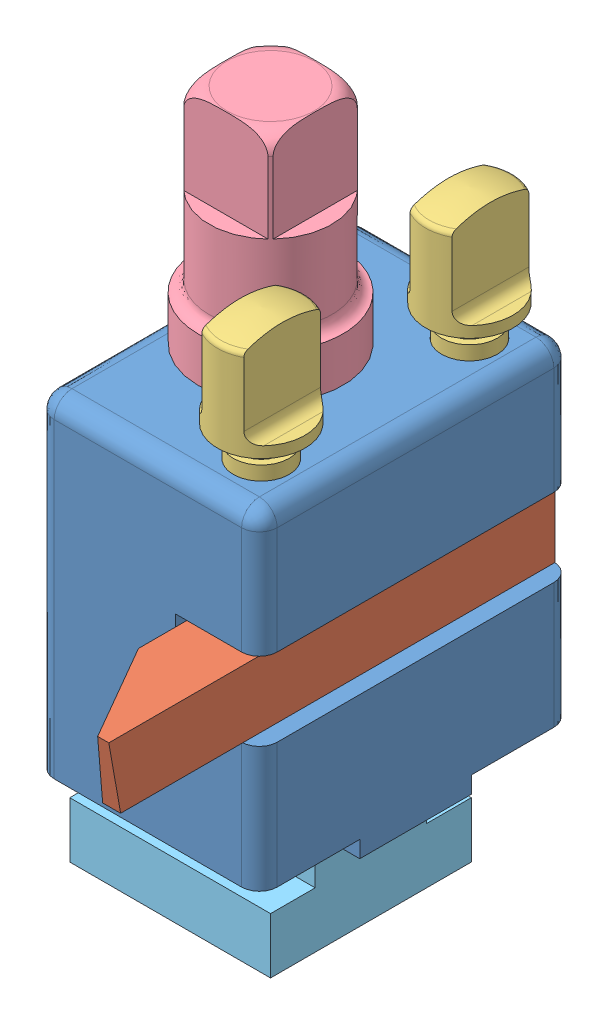
SolidWorks assembly Sub_Assembly_Tool_Post_R, configuration Default. Lengths in mm.
Overall size (34.92 96.23 63.5).
6 component instances, 5 part files, 13 mates.
Components (placement in the parent):
- Tool_Post-1: Tool_Post [Default] at (19.3679 28.1926 36.3512) size (31.75 49.21 44.45)
- Cutter-2: Cutter [Default] at (23.3366 22.6363 14.1262) x (-1 0 0) z (0 0 -1) size (9.53 9.53 63.5)
- Set_Screw-3: Set_Screw [Default] at (28.0991 32.1613 51.1678) size (12.45 38.14 12.45)
- Set_Screw-4: Set_Screw [Default] at (28.0991 32.1613 21.5345) size (12.45 38.14 12.45)
- Bolt-2: Bolt [Default] at (14.6054 -8.7168 36.3512) size (20.64 92.64 20.64)
- Tool_Block_Nut-2: Tool_Block_Nut [Default] at (14.6054 -12.3045 36.3512) size (28.57 11.91 28.57)
Mates (geometry in assembly coordinates):
- Distance2: distance = 0 mm aligned: plane of Cutter-2 through (32.8616 32.1613 14.1262) normal (0 0 -1); plane of Tool_Post-1 through (19.3679 28.1926 14.1262) normal (0 0 -1)
- Distance3: distance = 0 mm anti-aligned: plane of Cutter-2 through (23.3366 22.6363 14.1262) normal (0 -1 0); plane of Tool_Post-1 through (35.2429 22.6363 58.5762) normal (0 1 0)
- Distance4: distance = 0 mm anti-aligned: plane of Tool_Post-1 through (23.3366 33.7488 58.5762) normal (1 0 0); plane of Cutter-2 through (23.3366 32.1613 14.1262) normal (-1 0 0)
- Concentric1: concentric anti-aligned: cylinder of Tool_Post-1 through (28.0991 2.3947 51.1678) axis (0 1 0) radius 3.9688; cylinder of Set_Screw-3 through (28.0991 32.1613 51.1678) axis (0 -1 0) radius 3.9688
- Distance5: distance = 0 mm anti-aligned: plane of Set_Screw-3 through (28.0991 32.1613 51.1678) normal (0 -1 0); plane of Cutter-2 through (23.3366 32.1613 14.1262) normal (0 1 0)
- Parallel1: parallel aligned: plane of Tool_Post-1 through (35.2429 51.6082 58.5762) normal (1 0 0); plane of Set_Screw-3 through (31.0836 59.1488 44.9448) normal (1 0 0)
- Concentric2: concentric anti-aligned: cylinder of Tool_Post-1 through (28.0991 2.3947 21.5345) axis (0 1 0) radius 3.9688; cylinder of Set_Screw-4 through (28.0991 32.1613 21.5345) axis (0 -1 0) radius 3.9688
- Coincident7: coincident anti-aligned: plane of Cutter-2 through (23.3366 32.1613 14.1262) normal (0 1 0); plane of Set_Screw-4 through (28.0991 32.1613 21.5345) normal (0 -1 0)
- Parallel2: parallel aligned: plane of Tool_Post-1 through (35.2429 51.6082 58.5762) normal (1 0 0); plane of Set_Screw-4 through (31.0836 59.1488 15.3115) normal (1 0 0)
- Concentric3: concentric anti-aligned: cylinder of Tool_Post-1 through (14.6054 2.3957 36.3512) axis (0 1 0) radius 6.331; cylinder of Bolt-2 through (14.6054 -8.7168 36.3512) axis (0 -1 0) radius 6.331
- Coincident9: coincident anti-aligned: plane of Tool_Post-1 through (35.2429 51.6082 58.5762) normal (0 1 0); plane of Bolt-2 through (24.9241 51.6082 36.3512) normal (0 -1 0)
- Concentric4: concentric anti-aligned: cylinder of Bolt-2 through (14.6054 -8.7168 36.3512) axis (0 -1 0) radius 6.331; cylinder of Tool_Block_Nut-2 through (14.6054 -12.3045 36.3512) axis (0 1 0) radius 6.331
- Distance6: distance = 2.794 mm anti-aligned: plane of Tool_Block_Nut-2 through (0.3179 -0.3983 28.4137) normal (0 1 0); plane of Tool_Post-1 through (3.4929 2.3957 44.2887) normal (0 -1 0)
